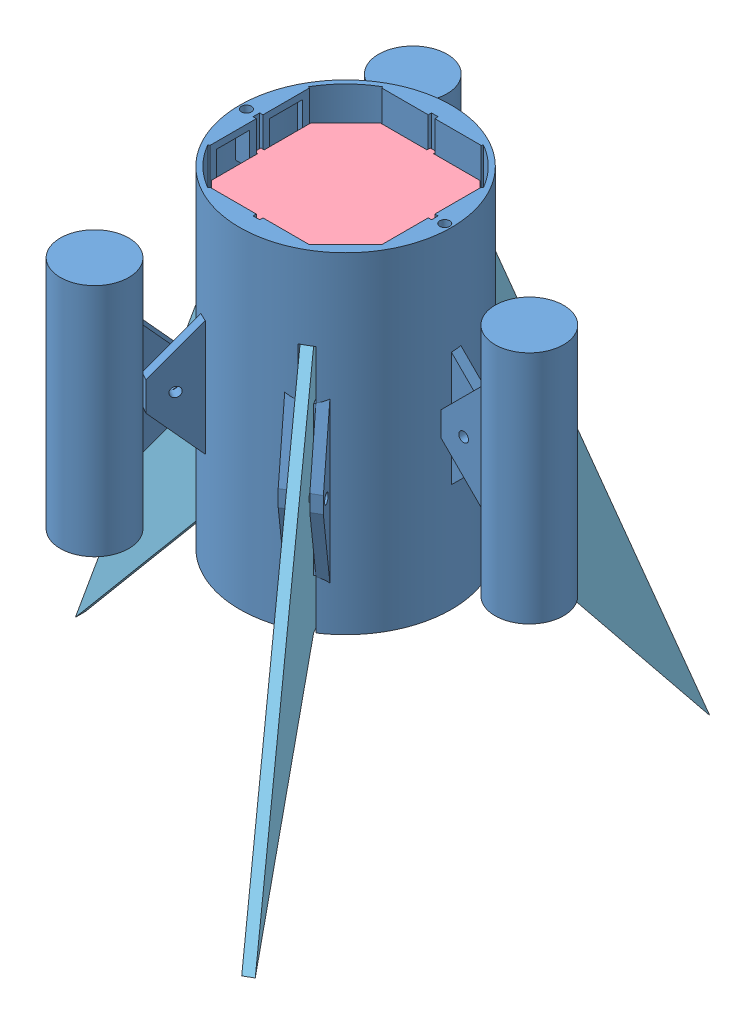
SolidWorks assembly RocketAssembly, configuration Default. Lengths in mm.
Overall size (146.11 157.45 140.43).
10 component instances, 5 part files, 19 mates.
Components (placement in the parent):
- Rocketbodies-1: Rocketbodies [Fuselage] at (42.2657 137.5967 45.4433) size (82 100 79.44)
- Rocketbodies-2: Rocketbodies [RocketBooster] at (14.4872 137.5967 93.5571) x (0.5 0 -0.866025) z (0.866025 0 0.5) size (34.04 70.99 20.68)
- Rocketbodies-3: Rocketbodies [RocketBooster] at (14.4872 137.5967 -2.6705) x (0.5 0 0.866025) z (-0.866025 0 0.5) size (34.04 70.99 20.68)
- Rocketbodies-4: Rocketbodies [RocketBooster] at (97.8227 137.5967 45.4433) x (-1 0 0) z (0 0 -1) size (34.04 70.99 20.68)
- Micro Servo FS90R Continuous-1: Micro Servo FS90R Continuous [Valor predeterminado] at (52.2657 153.9717 54.9241) x (0 -1 0) z (1 0 0) size (32 29 12)
- Arm-1: Arm [Default] at (54.7657 159.2217 43.3103) x (-0.585599 -0.810601 0) z (0.810601 -0.585599 0) size (6.03 2.03 32.92)
- Flat Thingy-1: Flat Thingy [Default] at (42.2657 177.5967 45.4433) size (53.21 1 53.21)
- Wings-1: Wings [Default] at (10.2657 87.5967 43.9433) x (1 0 0) z (0 -1 0) size (52.21 3 132.45)
- Wings-2: Wings [Default] at (56.9666 87.5967 73.9061) x (-0.5 0 -0.866025) z (0 -1 0) size (52.21 3 132.45)
- Wings-3: Wings [Default] at (59.5647 87.5967 18.4805) x (-0.5 0 0.866025) z (0 -1 0) size (52.21 3 132.45)
Mates (geometry in assembly coordinates):
- Parallel1: parallel anti-aligned: plane of Rocketbodies-1 through (57.2657 169.5967 52.9241) normal (0 -1 0); plane of Micro Servo FS90R Continuous-1 through (46.2657 165.2217 70.9241) normal (0 1 0)
- Parallel2: parallel anti-aligned: plane of Rocketbodies-1 through (57.2657 217.8647 71.4241) normal (0 0 -1); plane of Micro Servo FS90R Continuous-1 through (52.2657 153.9717 70.9241) normal (0 0 1)
- Coincident14: coincident anti-aligned: plane of Rocketbodies-1 through (57.2657 165.0967 52.9241) normal (0 0 1); plane of Micro Servo FS90R Continuous-1 through (52.2657 167.5967 52.9241) normal (0 0 -1)
- Concentric54: concentric aligned: cylinder of Rocketbodies-1 through (52.2657 167.5967 85.9155) axis (0 0 -1) radius 1.25; circle of Micro Servo FS90R Continuous-1
- Width3: width anti-aligned: plane of Wings-1 through (10.2657 87.5967 46.9433) normal (0 0 1); plane of Wings-1 through (10.2657 87.5967 43.9433) normal (0 0 -1); plane of Rocketbodies-1 through (10.3282 101.0245 47.4433) normal (0 0 -1); plane of Rocketbodies-1 through (10.3282 101.0245 43.4433) normal (0 0 1)
- Concentric56: concentric anti-aligned: cylinder of Rocketbodies-1 through (7.7657 125.0967 50.4433) axis (0 0 -1) radius 1.4732; cylinder of Wings-1 through (7.7657 125.0967 43.9433) axis (0 0 1) radius 1.4732
- Concentric57: concentric anti-aligned: cylinder of Rocketbodies-1 through (63.8458 125.0967 72.8212) axis (-0.866025 0 0.5) radius 1.4732; cylinder of Wings-2 through (58.2166 125.0967 76.0712) axis (0.866025 0 -0.5) radius 1.4732
- Width4: width anti-aligned: plane of Wings-2 through (56.9666 87.5967 73.9061) normal (-0.866025 0 0.5); plane of Wings-2 through (59.5647 87.5967 72.4061) normal (0.866025 0 -0.5); plane of Rocketbodies-1 through (56.5023 101.0245 74.102) normal (0.866025 0 -0.5); plane of Rocketbodies-1 through (59.9664 101.0245 72.102) normal (-0.866025 0 0.5)
- Parallel3: parallel aligned: plane of Rocketbodies-1 through (42.2657 87.5967 75.4433) normal (0 -1 0); plane of Wings-2 through (54.9666 87.5967 70.442) normal (0 -1 0)
- Coincident17: coincident aligned: plane of Rocketbodies-1 through (42.2657 87.5967 75.4433) normal (0 -1 0); plane of Wings-1 through (14.2657 87.5967 43.9433) normal (0 -1 0)
- Concentric58: concentric anti-aligned: cylinder of Rocketbodies-1 through (55.1855 125.0967 13.0654) axis (0.866025 0 0.5) radius 1.4732; cylinder of Wings-3 through (60.8147 125.0967 16.3154) axis (-0.866025 0 -0.5) radius 1.4732
- Width5: width anti-aligned: plane of Wings-3 through (59.5647 87.5967 18.4805) normal (0.866025 0 0.5); plane of Wings-3 through (56.9666 87.5967 16.9805) normal (-0.866025 0 -0.5); plane of Rocketbodies-1 through (59.9664 101.0245 18.7847) normal (-0.866025 0 -0.5); plane of Rocketbodies-1 through (56.5023 101.0245 16.7847) normal (0.866025 0 0.5)
- Parallel4: parallel aligned: plane of Rocketbodies-1 through (42.2657 87.5967 75.4433) normal (0 -1 0); plane of Wings-3 through (57.5647 87.5967 21.9446) normal (0 -1 0)
- Coincident18: coincident anti-aligned: plane of Rocketbodies-1 through (42.2657 177.5967 45.4433) normal (0 1 0); plane of Flat Thingy-1 through (42.2657 177.5967 45.4433) normal (0 -1 0)
- Concentric60: concentric anti-aligned: cylinder of Rocketbodies-1 through (42.2657 137.5967 45.4433) axis (0 -1 0) radius 32; cylinder of Rocketbodies-4 through (42.2657 125.0967 45.4433) axis (0 1 0) radius 32
- Concentric62: concentric anti-aligned: cylinder of Rocketbodies-1 through (42.2657 137.5967 45.4433) axis (0 -1 0) radius 32; cylinder of Rocketbodies-3 through (42.2657 125.0967 45.4433) axis (0 1 0) radius 32
- Concentric63: concentric anti-aligned: cylinder of Rocketbodies-1 through (42.2657 137.5967 45.4433) axis (0 -1 0) radius 32; cylinder of Rocketbodies-2 through (42.2657 125.0967 45.4433) axis (0 1 0) radius 32
- Width6: width anti-aligned: plane of Rocketbodies-1 through (43.2657 177.5967 18.4626) normal (0 0 1); plane of Flat Thingy-1 through (43.2657 177.5967 72.4241) normal (0 0 -1); plane of Rocketbodies-1 through (41.2657 177.5967 18.8367) normal (0 0 -1); plane of Flat Thingy-1 through (41.2657 177.5967 72.0499) normal (0 0 1)
- Width7: width aligned: plane of Rocketbodies-1 through (15.2849 177.5967 46.4433) normal (1 0 0); plane of Flat Thingy-1 through (69.2464 177.5967 46.4433) normal (-1 0 0); plane of Rocketbodies-1 through (68.8723 177.5967 44.4433) normal (1 0 0); plane of Flat Thingy-1 through (15.6591 177.5967 44.4433) normal (-1 0 0)
